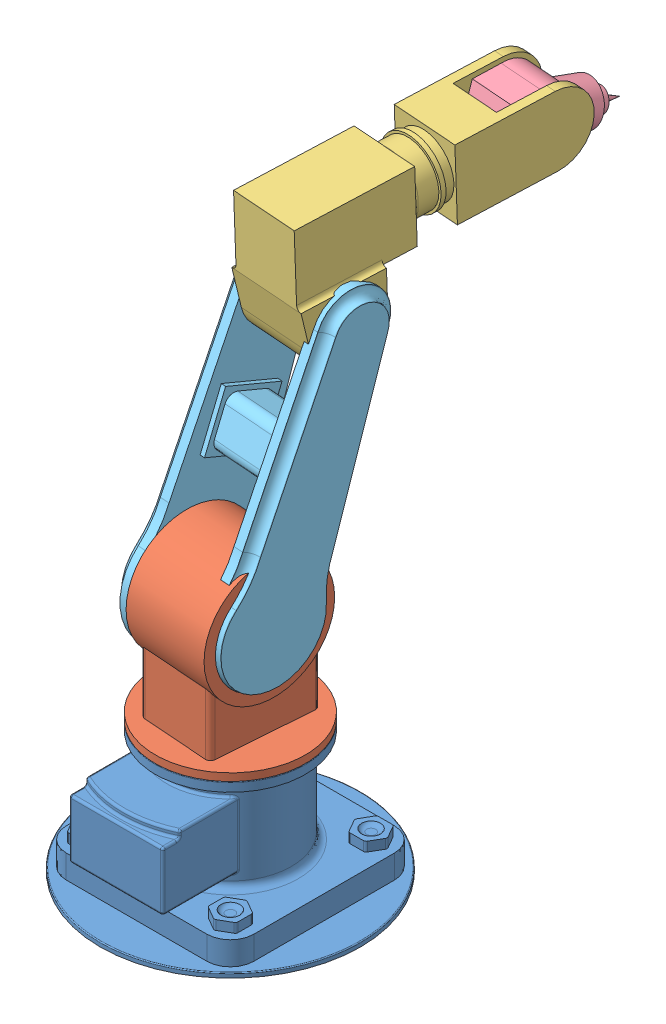
SolidWorks assembly Assem1, configuration Default. Lengths in mm.
Overall size (555 1209.76 1082.82).
5 component instances, 5 part files, 8 mates.
Components (placement in the parent):
- base of major project-1: base of major project [Default] at (148.2471 133.4948 468.0626) size (555 280 555)
- LINK 1 MAJOR PROJECT-1: LINK 1 MAJOR PROJECT [Default] at (148.2471 293.4948 468.0626) x (0.073814 0 -0.997272) z (0.997272 0 0.073814) size (320 466 320)
- link 3-1: link 3 [Default] at (144.0218 1239.5273 389.6731) x (0.073771 0.034035 -0.996694) z (0.997272 0 0.073814) size (595 297.5 160)
- 4-1: 4 [Default] at (182.383 1257.2258 -128.6079) x (0.070405 -0.30039 -0.951215) z (0.997272 0 0.073814) size (275 130 100)
- link 2-1: link 2 [Default] at (133.288 629.4948 466.9554) x (0.069129 -0.35058 -0.933978) z (-0.025878 -0.936533 0.349624) size (250 230.14 700)
Mates (geometry in assembly coordinates):
- Concentric2: concentric anti-aligned: cylinder of base of major project-1 through (148.2471 213.4948 468.0626) axis (0 1 0) radius 100; cylinder of LINK 1 MAJOR PROJECT-1 through (148.2471 429.4948 468.0626) axis (0 -1 0) radius 160
- Coincident1: coincident anti-aligned: plane of base of major project-1 through (148.2471 413.4948 468.0626) normal (0 1 0); plane of LINK 1 MAJOR PROJECT-1 through (148.2471 413.4948 468.0626) normal (0 -1 0)
- Coincident2: coincident anti-aligned: circle of LINK 1 MAJOR PROJECT-1; cylinder of link 2-1 through (208.0834 629.4948 472.4915) axis (-0.997272 0 -0.073814) radius 75
- Coincident3: coincident anti-aligned: plane of LINK 1 MAJOR PROJECT-1 through (58.4926 629.4948 461.4193) normal (-0.997272 0 -0.073814); plane of link 2-1 through (41.3772 857.2172 692.6581) normal (0.997272 0 0.073814)
- Coincident4: coincident anti-aligned: circle of link 3-1; cylinder of link 2-1 through (221.0223 1097.7611 297.6795) axis (-0.997272 0 -0.073814) radius 50
- Coincident5: coincident anti-aligned: plane of link 3-1 through (71.4315 1097.7611 286.6074) normal (-0.997272 0 -0.073814); plane of link 2-1 through (41.3772 857.2172 692.6581) normal (0.997272 0 0.073814)
- Coincident6: coincident aligned: circle of link 3-1; cylinder of 4-1 through (232.2466 1257.2258 -124.9172) axis (-0.997272 0 -0.073814) radius 50
- Coincident7: coincident anti-aligned: plane of link 3-1 through (132.5194 1257.2258 -132.2986) normal (0.997272 0 0.073814); plane of 4-1 through (132.5194 1257.2258 -132.2986) normal (-0.997272 0 -0.073814)
